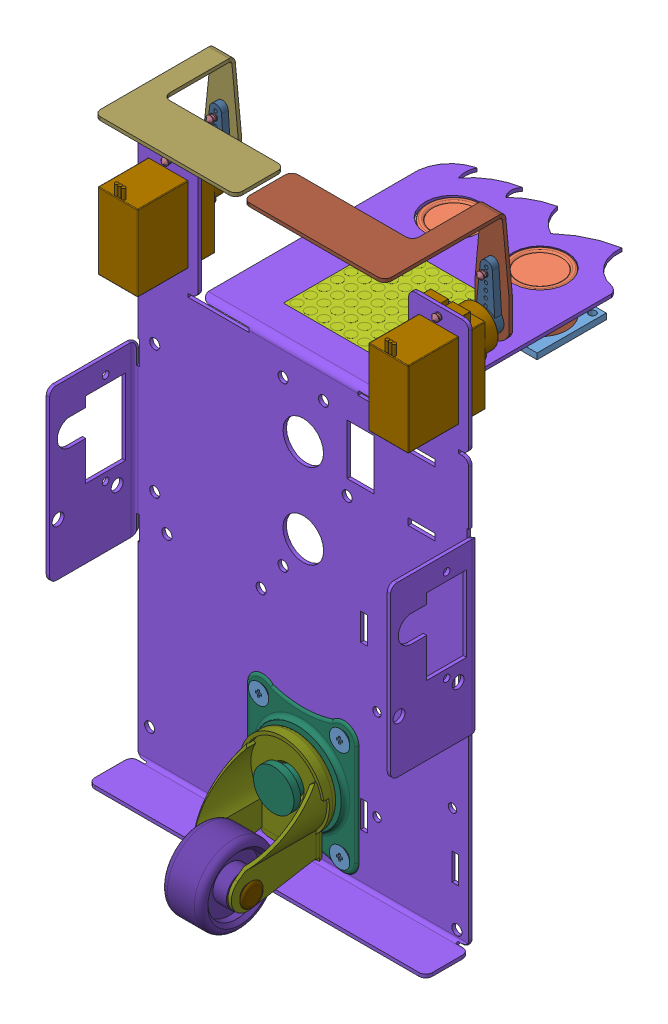
SolidWorks assembly Ensamblaje4, configuration Predeterminado. Lengths in mm.
Overall size (102.01 183.65 112.62).
42 component instances, 19 part files, 12 mates.
Components (placement in the parent):
- HC-SR04 Ping Sensor-1: HC-SR04 Ping Sensor [Default] at (150.9372 -204.3854 82.6556) x (0 0 -1) z (0 1 0) size (25.18 45 18.07)
  - PCB-1: PCB [Default] at origin size (20.5 45 1.75)
  - Transducer-1: Transducer [Default] at (0 -13.16 13.25) x (1 0 0) z (0 -1 0) size (15.88 12 15.88)
  - Transducer-2: Transducer [Default] at (0 12.34 13.25) x (1 0 0) z (0 -1 0) size (15.88 12 15.88)
  - 3 Pin Header 90 Degree-1: 3 Pin Header 90 Degree [Default] at (8.4275 0 -1.25) x (-1 0 0) z (0 -1 0) size (8 7.82 10)
  - 14 Pin SMT-1: 14 Pin SMT [Default] at (-0.35 -18.5 -0.85) x (0 -1 0) z (1 0 0) size (6 1.6 8.8)
  - 14 Pin SMT-2: 14 Pin SMT [Default] at (0 -0.3826 -0.85) x (1 0 0) z (0 1 0) size (6 1.6 8.8)
  - 14 Pin SMT-3: 14 Pin SMT [Default] at (0 17.5274 -0.85) x (1 0 0) z (0 1 0) size (6 1.6 8.8)
  - Cap1 SMT-1: Cap1 SMT [Default] at (-1.755 7.4774 -0.9689) x (0 1 0) z (-1 0 0) size (4.5 1.84 1.75)
  - Cap1 SMT-2: Cap1 SMT [Default] at (6.835 7.4774 -0.9689) x (0 1 0) z (-1 0 0) size (4.5 1.84 1.75)
  - Cap1 SMT-3: Cap1 SMT [Default] at (-6.835 7.4774 -0.9689) x (0 1 0) z (-1 0 0) size (4.5 1.84 1.75)
  - Cap1 SMT-4: Cap1 SMT [Default] at (4.295 7.4774 -0.9689) x (0 1 0) z (-1 0 0) size (4.5 1.84 1.75)
  - Cap1 SMT-5: Cap1 SMT [Default] at (1.755 7.4774 -0.9689) x (0 1 0) z (-1 0 0) size (4.5 1.84 1.75)
  - Cap1 SMT-6: Cap1 SMT [Default] at (-4.295 7.4774 -0.9689) x (0 1 0) z (-1 0 0) size (4.5 1.84 1.75)
  - HC-SR04 Crystal-1: HC-SR04 Crystal [Default] at (-8.3 0 1.75) x (0 -1 0) z (0 0 1) size (10 3.5 2.7)
- max7219_compact_board-1: max7219_compact_board [Predeterminado] at (157.5972 -204.8354 113.6556) x (1 0 0) z (0 1 0) size (34 32 21.83)
- DYOR_LEDMatrix_MetalSheet_Pusher-1: DYOR_LEDMatrix_MetalSheet_Pusher [Predeterminado] at (90.3982 -139.1144 139.7994) size (102.01 161.18 100.67)
- PU-1: PU [Predeterminado] at (-16.2984 3.5 -1.0225) size (91.94 49.57 37.38)
  - sg90-1: sg90 [Default] at (201.5956 -166.7354 155.7219) x (0 -1 0) z (1 0 0) size (31.9 29.9 11.8)
  - sg90-2: sg90 [Default] at (121.452 -166.7354 155.7219) x (0 -1 0) z (1 0 0) size (31.9 29.9 11.8)
  - SG90 plastic Horn-1: SG90 plastic Horn [Default] at (127.352 -172.6354 127.0219) x (0.017141 0.999853 0) z (-0.999853 0.017141 0) size (19.4 4 7.07)
  - SG90 plastic Horn-2: SG90 plastic Horn [Default] at (207.4956 -172.6354 127.0219) x (0.020276 0.999794 0) z (-0.999794 0.020276 0) size (19.4 4 7.07)
  - Pusher_left-1: Pusher_left [Predeterminado] at (252.6438 -158.8738 124.0219) x (-1 0 0) z (0 0 -1) size (44 33.65 35.77)
  - Pusher_right-1: Pusher_right [Predeterminado] at (82.2037 -158.8738 125.0219) size (44 33.65 35.77)
  - M2x6 SelfTap Screw-1: M2x6 SelfTap Screw [Predeterminado] at (207.4956 -164.3354 136.8219) x (-0.923728 -0.383049 0) z (0 0 -1) size (3.4 3.28 6)
  - M2x6 SelfTap Screw-2: M2x6 SelfTap Screw [Predeterminado] at (207.4956 -191.6354 136.3219) x (-0.923728 -0.383049 0) z (0 0 -1) size (3.4 3.28 6)
  - M2x6 SelfTap Screw-3: M2x6 SelfTap Screw [Predeterminado] at (127.352 -164.3354 136.8219) x (-0.993348 0.115149 0) z (0 0 -1) size (3.4 3.28 6)
  - M2x6 SelfTap Screw-4: M2x6 SelfTap Screw [Predeterminado] at (127.352 -191.6354 136.8219) x (-0.923728 -0.383049 0) z (0 0 -1) size (3.4 3.28 6)
  - (M2_3_mm)_90116A007_METRIC 316 SS PAN HEAD PHILLIPS MACHINE SCREW-1: (M2_3_mm)_90116A007_METRIC 316 SS PAN HEAD PHILLIPS MACHINE SCREW [90116A007] at (127.352 -172.6354 127.0219) x (-0.923728 -0.383049 0) z (0 0 -1) size (4 4 4.68)
  - (M2_3_mm)_90116A007_METRIC 316 SS PAN HEAD PHILLIPS MACHINE SCREW-2: (M2_3_mm)_90116A007_METRIC 316 SS PAN HEAD PHILLIPS MACHINE SCREW [90116A007] at (207.4956 -172.6354 127.0219) x (-0.923728 -0.383049 0) z (0 0 -1) size (4 4 4.68)
  - M2x6 SelfTap Screw-5: M2x6 SelfTap Screw [Predeterminado] at (127.352 -160.1354 123.5219) x (-0.923728 -0.383049 0) z (0 0 -1) size (3.4 3.28 6)
  - M2x6 SelfTap Screw-6: M2x6 SelfTap Screw [Predeterminado] at (207.4956 -160.1354 123.5219) x (-0.923728 -0.383049 0) z (0 0 -1) size (3.4 3.28 6)
- CA-1: CA [Predeterminado] at (0 -1.6781 0) size (33 45.94 43.84)
  - Caster Wheel-1: Caster Wheel [Default] at (197.1109 -294.8334 184.5177) x (0 1 0) z (-1 0 0) size (45.94 37.15 33)
    - caster holder-1: caster holder [Default] at (-24.0751 44.7184 29.5137) x (1 0 0) z (0 0 -1) size (39 8.84 33)
    - holder-1: holder [Default] at (-1.5751 42.9484 46.0137) x (0 0 1) z (1 0 0) size (25 28.07 31.31)
    - caster wheel-1: caster wheel [Default] at (-15.6961 19.9484 46.0137) x (0.997275 0.073773 0) z (0 0 1) size (23 23 14)
    - Part4-1: Part4 [Default] at (-15.6961 19.9484 55.0137) x (-0.978448 0.206495 0) z (0 0 -1) size (7 7 20)
  - M4x8 SelfTap Screw-1: M4x8 SelfTap Screw [Predeterminado] at (139.0972 -281.4086 141.0494) size (6 6 8)
  - M4x8 SelfTap Screw-2: M4x8 SelfTap Screw [Predeterminado] at (163.0972 -281.4086 141.0494) size (6 6 8)
  - M4x8 SelfTap Screw-3: M4x8 SelfTap Screw [Predeterminado] at (139.0972 -311.4086 141.0494) size (6 6 8)
  - M4x8 SelfTap Screw-4: M4x8 SelfTap Screw [Predeterminado] at (163.0972 -311.4086 141.0494) size (6 6 8)
Mates (geometry in assembly coordinates):
- Concéntrica280: concentric: circle of HC-SR04 Ping Sensor-1/Transducer-1; circle of DYOR_LEDMatrix_MetalSheet_Pusher-1
- Paralelo98: parallel: plane of HC-SR04 Ping Sensor-1/PCB-1 through (128.4372 -202.6354 92.9056) normal (0 0 1); plane of DYOR_LEDMatrix_MetalSheet_Pusher-1 through (184.2972 -190.1354 138.7994) normal (0 0 -1)
- Coincidente470: coincident: plane of HC-SR04 Ping Sensor-1/Transducer-1 through (164.0972 -190.6354 74.7156) normal (0 1 0); plane of DYOR_LEDMatrix_MetalSheet_Pusher-1 through (184.2972 -190.6354 137.6556) normal (0 1 0)
- Coincidente466: coincident: plane of max7219_compact_board-1 through (135.0972 -190.6354 97.6556) normal (0 0 -1); plane of DYOR_LEDMatrix_MetalSheet_Pusher-1 through (167.0972 -191.6354 97.6556) normal (0 0 1)
- Coincidente467: coincident: plane of max7219_compact_board-1 through (167.0972 -190.6354 97.6556) normal (1 0 0); plane of DYOR_LEDMatrix_MetalSheet_Pusher-1 through (167.0972 -191.6354 97.6556) normal (-1 0 0)
- Coincidente468: coincident: plane of max7219_compact_board-1 through (157.5972 -190.6354 113.6556) normal (0 1 0); plane of DYOR_LEDMatrix_MetalSheet_Pusher-1 through (184.2972 -190.6354 137.6556) normal (0 1 0)
- Coincidente471: coincident: plane of DYOR_LEDMatrix_MetalSheet_Pusher-1 through (184.2972 -190.1354 138.7994) normal (0 0 -1); plane of PU-1/sg90-1 through (185.2972 -158.5354 138.7994) normal (0 0 1)
- Concéntrica281: concentric: circle of DYOR_LEDMatrix_MetalSheet_Pusher-1; circle of PU-1/M2x6 SelfTap Screw-1
- Concéntrica282: concentric: circle of DYOR_LEDMatrix_MetalSheet_Pusher-1; circle of PU-1/M2x6 SelfTap Screw-2
- Coincidente494: coincident: plane of DYOR_LEDMatrix_MetalSheet_Pusher-1 through (184.2972 -190.1354 139.7994) normal (0 0 1); plane of CA-1/Caster Wheel-1/caster holder-1 through (151.0972 -253.2884 139.7994) normal (0 0 -1)
- Concéntrica301: concentric: circle of DYOR_LEDMatrix_MetalSheet_Pusher-1; circle of CA-1/M4x8 SelfTap Screw-2
- Concéntrica302: concentric: circle of DYOR_LEDMatrix_MetalSheet_Pusher-1; circle of CA-1/M4x8 SelfTap Screw-4
